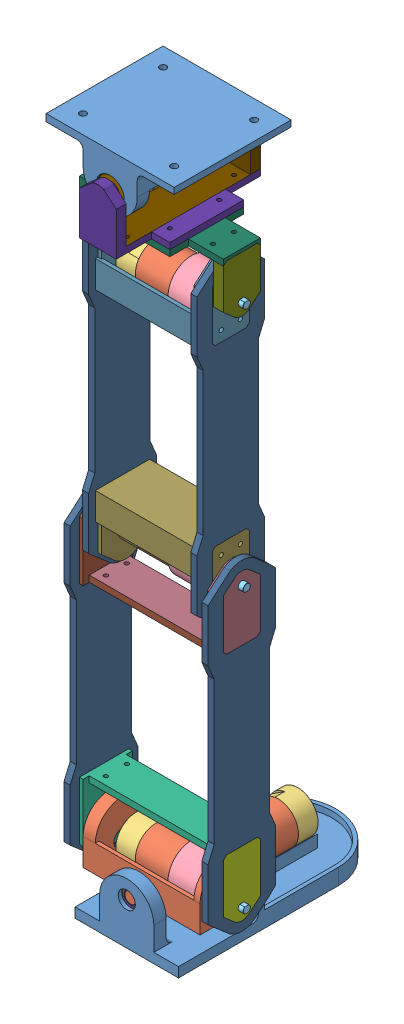
SolidWorks assembly Leg Left, configuration Default. Lengths in mm.
Overall size (121 569.75 211.17).
57 component instances, 20 part files, 77 mates.
Components (placement in the parent):
- Foot-1: Foot [Default] at origin size (89.58 49 186.67)
- Motor-1: Motor [Default] at (14.2667 22.6871 -73.752) x (-1 0 0) z (0 0 1) size (45.64 45.64 90) (flexible)
  - Motor Proper-1: Motor Proper [Default] at (14.2667 22.6871 35.252) x (0.971375 -0.237549 0) z (0 0 1) size (33 33 29)
  - Motor Encoder-1: Motor Encoder [Default] at (14.2667 22.6871 20.752) x (0.839139 0.543917 0) z (0 0 1) size (33 33 16)
  - Motor Gearbox-1: Motor Gearbox [Default] at (14.2667 22.6871 49.752) size (38 38 30)
  - Motor Shaft-1: Motor Shaft [Default] at (14.2667 15.6871 60.752) size (6 6 34)
- Motor-2: Motor [Default] at (-31.252 -0.6871 50.2667) x (0 0 -1) z (1 0 0) size (45.64 45.64 90) (flexible)
  - Motor Proper-1: Motor Proper [Default] at (14.2667 22.6871 35.252) x (0.971375 -0.237549 0) z (0 0 1) size (33 33 29)
  - Motor Encoder-1: Motor Encoder [Default] at (14.2667 22.6871 20.752) x (0.839139 0.543917 0) z (0 0 1) size (33 33 16)
  - Motor Gearbox-1: Motor Gearbox [Default] at (14.2667 22.6871 49.752) size (38 38 30)
  - Motor Shaft-1: Motor Shaft [Default] at (14.2667 15.6871 60.752) x (-1 0 0) z (0 0 1) size (6 6 34)
- Ankle Bearing-1: Ankle Bearing [Default] at (-57.5 22 36) x (0 0 -1) z (1 0 0) size (40 60 109)
- Ankle DShaft-1: Ankle DShaft [Default] at (59.5 22 36) x (0 0 1) z (-1 0 0) size (40 57.5 109)
- Bearing-1: Bearing [Default] at (-5.4134 7 64) size (30.72 30.72 6)
  - Bearing Inner-1: Bearing Inner [Default] at (5.4134 0 0) x (0.99329 0.115652 0) z (0 0 1) size (13.2 13.2 6)
  - Bearing Outer-1: Bearing Outer [Default] at (5.4134 0 0) x (0.586238 0.810139 0) z (0 0 1) size (22 22 6)
- Bearing-2: Bearing [Default] at (-43.5 14.965 30.5867) x (0 0.00646 0.999979) z (-1 0 0) size (30.72 30.72 6)
  - Bearing Inner-1: Bearing Inner [Default] at (5.4134 0 0) x (0.99329 0.115652 0) z (0 0 1) size (13.2 13.2 6)
  - Bearing Outer-1: Bearing Outer [Default] at (5.4134 0 0) x (0.586238 0.810139 0) z (0 0 1) size (22 22 6)
- Thigh and Shin-1: Thigh and Shin [Default] at (59.5 23.6603 36) x (0 0 1) z (-1 0 0) size (55 261.21 5)
- Thigh and Shin-2: Thigh and Shin [Default] at (-52.5 23.6603 36) x (0 0 1) z (-1 0 0) size (55 261.21 5)
- Knee Bearing-1: Knee Bearing [Default] at (-57.5 234.2132 36) x (0 0 1) z (1 0 0) size (40 60 109)
- Bearing-3: Bearing [Default] at (-40.5 241.2132 30.5866) x (0 0 1) z (-1 0 0) size (30.72 30.72 6)
  - Bearing Inner-1: Bearing Inner [Default] at (5.4134 0 0) x (0.99329 0.115652 0) z (0 0 1) size (13.2 13.2 6)
  - Bearing Outer-1: Bearing Outer [Default] at (5.4134 0 0) x (0.586238 0.810139 0) z (0 0 1) size (22 22 6)
- Knee-1: Knee [Default] at (50.5 248.2132 36) x (0 0 -1) z (-1 0 0) size (44 57.5 95)
- Knee DShaft-1: Knee DShaft [Default] at (59.5 234.2132 36) x (0 0 -1) z (-1 0 0) size (40 57.5 109)
- Motor-3: Motor [Default] at (-31.252 225.5261 50.2667) x (0 0 -1) z (1 0 0) size (45.64 45.64 90) (flexible)
  - Motor Proper-1: Motor Proper [Default] at (14.2667 22.6871 35.252) x (0.971375 -0.237549 0) z (0 0 1) size (33 33 29)
  - Motor Encoder-1: Motor Encoder [Default] at (14.2667 22.6871 20.752) x (0.839139 0.543917 0) z (0 0 1) size (33 33 16)
  - Motor Gearbox-1: Motor Gearbox [Default] at (14.2667 22.6871 49.752) size (38 38 30)
  - Motor Shaft-1: Motor Shaft [Default] at (14.2667 15.6871 60.752) size (6 6 34)
- Thigh and Shin-3: Thigh and Shin [Default] at (50.5 236.3735 36) x (0 0 1) z (-1 0 0) size (55 261.21 5)
- Thigh and Shin-4: Thigh and Shin [Default] at (-37.5 236.3735 36) x (0 0 1) z (-1 0 0) size (55 261.21 5)
- Hip A-1: Hip A [Default] at (50.5 433.4264 36) x (0 0 1) z (-1 0 0) size (44 57.5 95)
- Hip Bearing A-1: Hip Bearing A [Default] at (-57.5 447.4264 36) x (0 0 -1) z (1 0 0) size (60 47.81 117)
- Hip DShaft A-1: Hip DShaft A [Default] at (59.5 447.4264 36) x (0 0 1) z (-1 0 0) size (30 45 109)
- Bearing-4: Bearing [Default] at (-40.5 440.4264 30.5866) x (0 0 1) z (-1 0 0) size (30.72 30.72 6)
  - Bearing Inner-1: Bearing Inner [Default] at (5.4134 0 0) x (0.99329 0.115652 0) z (0 0 1) size (13.2 13.2 6)
  - Bearing Outer-1: Bearing Outer [Default] at (5.4134 0 0) x (0.586238 0.810139 0) z (0 0 1) size (22 22 6)
- Motor-4: Motor [Default] at (-31.252 456.1135 21.7333) x (0 0 1) z (1 0 0) size (45.64 45.64 90) (flexible)
  - Motor Proper-1: Motor Proper [Default] at (14.2667 22.6871 35.252) x (0.971375 -0.237549 0) z (0 0 1) size (33 33 29)
  - Motor Encoder-1: Motor Encoder [Default] at (14.2667 22.6871 20.752) x (0.839139 0.543917 0) z (0 0 1) size (33 33 16)
  - Motor Gearbox-1: Motor Gearbox [Default] at (14.2667 22.6871 49.752) size (38 38 30)
  - Motor Shaft-1: Motor Shaft [Default] at (14.2667 15.6871 60.752) size (6 6 34)
- Bearing-5: Bearing [Default] at (-4.4134 512.9264 80.5) size (30.72 30.72 6)
  - Bearing Inner-1: Bearing Inner [Default] at (5.4134 0 0) x (0.99329 0.115652 0) z (0 0 1) size (13.2 13.2 6)
  - Bearing Outer-1: Bearing Outer [Default] at (5.4134 0 0) x (0.586238 0.810139 0) z (0 0 1) size (22 22 6)
- Hip Bearing B-1: Hip Bearing B [Default] at (1 505.9264 94.5) x (1 0 0) z (0 0 -1) size (60 45.31 117)
- Hip DShaft B-1: Hip DShaft B [Default] at (1 505.9264 -22.5) x (-1 0 0) z (0 0 1) size (30 42.5 109)
- Motor-5: Motor [Default] at (15.2667 497.2393 68.252) x (-1 0 0) z (0 0 -1) size (45.64 45.64 90) (flexible)
  - Motor Proper-1: Motor Proper [Default] at (14.2667 22.6871 35.252) x (0.971375 -0.237549 0) z (0 0 1) size (33 33 29)
  - Motor Encoder-1: Motor Encoder [Default] at (14.2667 22.6871 20.752) x (0.839139 0.543917 0) z (0 0 1) size (33 33 16)
  - Motor Gearbox-1: Motor Gearbox [Default] at (14.2667 22.6871 49.752) size (38 38 30)
  - Motor Shaft-1: Motor Shaft [Default] at (14.2667 15.6871 60.752) size (6 6 34)
- Hip B-1: Hip B [Default] at (1 519.9264 -10.5) x (-1 0 0) z (0 0 1) size (104 44 95)
- Ankle Left-1: Ankle Left [Default] at (47.5 22 36) x (0 0 -1) z (1 0 0) size (54 47.05 95)
Mates (geometry in assembly coordinates):
- Coincident3: coordinate: point of Foot-1; point of assembly
- Concentric1: concentric aligned: cylinder of Foot-1 through (0 7 5) axis (0 0 -1) radius 7.25; cylinder of Motor-1/Motor Gearbox-1 through (0 7 6) axis (0 0 -1) radius 7
- Concentric2: concentric anti-aligned: cylinder of Foot-1 through (7.75 -13.4234 0) axis (0 0 -1) radius 1.7; cylinder of Motor-1/Motor Gearbox-1 through (7.75 -13.4234 0) axis (0 0 1) radius 1.7
- Coincident4: coincident anti-aligned: plane of Foot-1 through (0 0 0) normal (0 0 -1); plane of Motor-1/Motor Gearbox-1 through (0 0 0) normal (0 0 1)
- Concentric6: concentric anti-aligned: cylinder of Motor-2/Motor Shaft-1 through (51.5 15 36) axis (-1 0 0) radius 3; cylinder of Ankle DShaft-1 through (51.5 15 36) axis (1 0 0) radius 3
- Coincident9: coincident anti-aligned: plane of Foot-1 through (0 7 67) normal (0 0 -1); plane of Bearing-1/Bearing Outer-1 through (0 7 67) normal (0 0 1)
- Concentric7: concentric aligned: cylinder of Foot-1 through (0 7 67) axis (0 0 -1) radius 11; cylinder of Bearing-1/Bearing Outer-1 through (0 7 67) axis (0 0 -1) radius 11
- Concentric10: concentric anti-aligned: cylinder of Ankle Bearing-1 through (-41.5 15 36) axis (-1 0 0) radius 5; cylinder of Bearing-2/Bearing Inner-1 through (-46.5 15 36) axis (1 0 0) radius 5
- Coincident11: coincident anti-aligned: plane of Motor-2/Motor Shaft-1 through (63.5 17.5 36) normal (0 1 0); plane of Ankle DShaft-1 through (51.5 17.5 36) normal (0 -1 0)
- Concentric11: concentric aligned: cylinder of Ankle Bearing-1 through (44.5 60 44.5) axis (0 1 0) radius 1.6; cylinder of Ankle DShaft-1 through (44.5 57.5 44.5) axis (0 1 0) radius 1.6
- Coincident12: coincident anti-aligned: plane of Motor-2/Motor Shaft-1 through (51.5 15 36) normal (1 0 0); plane of Ankle DShaft-1 through (51.5 22 36) normal (-1 0 0)
- Coincident13: coincident anti-aligned: plane of Ankle Bearing-1 through (-52.5 57.5 48.5) normal (0 1 0); plane of Thigh and Shin-2 through (-57.5 57.5 36) normal (0 -1 0)
- Coincident14: coincident anti-aligned: plane of Ankle Bearing-1 through (-49.5 22 21) normal (0 0 -1); plane of Thigh and Shin-2 through (-57.5 23.6603 21) normal (0 0 1)
- Coincident15: coincident anti-aligned: plane of Ankle Bearing-1 through (-52.5 15 36) normal (-1 0 0); plane of Thigh and Shin-2 through (-52.5 23.6603 36) normal (1 0 0)
- Coincident16: coincident anti-aligned: plane of Ankle DShaft-1 through (-49.5 57.5 36) normal (0 1 0); plane of Thigh and Shin-1 through (54.5 57.5 36) normal (0 -1 0)
- Coincident18: coincident anti-aligned: plane of Ankle DShaft-1 through (51.5 22 51) normal (0 0 1); plane of Thigh and Shin-1 through (54.5 23.6603 51) normal (0 0 -1)
- Coincident19: coincident anti-aligned: plane of Ankle DShaft-1 through (54.5 15 36) normal (1 0 0); plane of Thigh and Shin-1 through (54.5 23.6603 36) normal (-1 0 0)
- Parallel5: parallel anti-aligned: plane of Foot-1 through (-22 -19 70) normal (0 1 0); plane of Ankle DShaft-1 through (-49.5 55 36) normal (0 -1 0)
- Coincident27: coincident anti-aligned: plane of Thigh and Shin-1 through (54.5 23.6603 21) normal (0 0 1); plane of Knee DShaft-1 through (51.5 234.2132 21) normal (0 0 -1)
- Coincident28: coincident anti-aligned: plane of Thigh and Shin-1 through (54.5 198.7132 36) normal (0 1 0); plane of Knee DShaft-1 through (-49.5 198.7132 36) normal (0 -1 0)
- Coincident29: coincident anti-aligned: plane of Thigh and Shin-1 through (54.5 23.6603 36) normal (-1 0 0); plane of Knee DShaft-1 through (54.5 241.2132 36) normal (1 0 0)
- Coincident30: coincident anti-aligned: plane of Thigh and Shin-2 through (-57.5 23.6603 21) normal (0 0 1); plane of Knee Bearing-1 through (-49.5 236.7132 21) normal (0 0 -1)
- Concentric12: concentric aligned: cylinder of Knee Bearing-1 through (-42.5 198.7132 27.5) axis (0 -1 0) radius 1.6; cylinder of Knee DShaft-1 through (-42.5 198.7132 27.5) axis (0 -1 0) radius 1.6
- Coincident32: coincident anti-aligned: plane of Knee-1 through (42.5 248.2132 36) normal (-1 0 0); plane of Motor-3/Motor Gearbox-1 through (42.5 248.2132 36) normal (1 0 0)
- Concentric14: concentric anti-aligned: cylinder of Knee-1 through (45.5 241.2132 36) axis (1 0 0) radius 7.25; cylinder of Motor-3/Motor Gearbox-1 through (48.5 241.2132 36) axis (-1 0 0) radius 7
- Concentric15: concentric aligned: cylinder of Knee-1 through (50.5 261.6366 43.75) axis (1 0 0) radius 1.7; cylinder of Motor-3/Motor Gearbox-1 through (42.5 261.6366 43.75) axis (1 0 0) radius 1.7
- Concentric17: concentric anti-aligned: cylinder of Bearing-3/Bearing Outer-1 through (-43.5 241.2132 36) axis (1 0 0) radius 11; cylinder of Knee-1 through (-37.5 241.2132 36) axis (-1 0 0) radius 11
- Coincident33: coincident anti-aligned: plane of Bearing-3/Bearing Outer-1 through (-37.5 241.2132 36) normal (1 0 0); plane of Knee-1 through (-37.5 241.2132 36) normal (-1 0 0)
- Concentric18: concentric anti-aligned: cylinder of Knee DShaft-1 through (51.5 241.2132 36) axis (1 0 0) radius 3; cylinder of Motor-3/Motor Shaft-1 through (51.5 241.2132 36) axis (-1 0 0) radius 3
- Coincident34: coincident anti-aligned: plane of Knee DShaft-1 through (51.5 238.7132 36) normal (0 1 0); plane of Motor-3/Motor Shaft-1 through (63.5 238.7132 36) normal (0 -1 0)
- Coincident35: coincident anti-aligned: plane of Knee DShaft-1 through (51.5 234.2132 36) normal (-1 0 0); plane of Motor-3/Motor Shaft-1 through (51.5 241.2132 36) normal (1 0 0)
- Parallel6: parallel aligned: plane of Foot-1 through (-22 -19 70) normal (0 1 0); plane of Knee-1 through (45.5 270.2132 14) normal (0 1 0)
- Coincident37: coincident anti-aligned: plane of Knee-1 through (45.5 248.2132 51) normal (0 0 1); plane of Thigh and Shin-3 through (45.5 236.3735 51) normal (0 0 -1)
- Coincident38: coincident anti-aligned: plane of Knee-1 through (45.5 270.2132 14) normal (0 1 0); plane of Thigh and Shin-3 through (45.5 270.2132 36) normal (0 -1 0)
- Coincident40: coincident anti-aligned: plane of Knee-1 through (45.5 248.2132 36) normal (1 0 0); plane of Thigh and Shin-3 through (45.5 236.3735 36) normal (-1 0 0)
- Coincident41: coincident anti-aligned: plane of Knee-1 through (-44.5 248.2132 21) normal (0 0 -1); plane of Thigh and Shin-4 through (-42.5 236.3735 21) normal (0 0 1)
- Coincident42: coincident anti-aligned: plane of Knee-1 through (45.5 270.2132 14) normal (0 1 0); plane of Thigh and Shin-4 through (-42.5 270.2132 36) normal (0 -1 0)
- Coincident43: coincident anti-aligned: plane of Knee-1 through (-37.5 248.2132 36) normal (-1 0 0); plane of Thigh and Shin-4 through (-37.5 236.3735 36) normal (1 0 0)
- Coincident45: coincident anti-aligned: plane of Thigh and Shin-3 through (45.5 236.3735 51) normal (0 0 -1); plane of Hip A-1 through (45.5 433.4264 51) normal (0 0 1)
- Coincident46: coincident anti-aligned: plane of Thigh and Shin-3 through (45.5 411.4264 36) normal (0 1 0); plane of Hip A-1 through (45.5 411.4264 58) normal (0 -1 0)
- Concentric19: concentric anti-aligned: cylinder of Hip A-1 through (-37.5 440.4264 36) axis (-1 0 0) radius 11; cylinder of Bearing-4/Bearing Outer-1 through (-43.5 440.4264 36) axis (1 0 0) radius 11
- Coincident47: coincident anti-aligned: plane of Hip A-1 through (-37.5 440.4264 36) normal (-1 0 0); plane of Bearing-4/Bearing Outer-1 through (-37.5 440.4264 36) normal (1 0 0)
- Concentric20: concentric anti-aligned: cylinder of Hip A-1 through (45.5 440.4264 36) axis (1 0 0) radius 7.25; cylinder of Motor-4/Motor Gearbox-1 through (48.5 440.4264 36) axis (-1 0 0) radius 7
- Concentric21: concentric aligned: cylinder of Hip A-1 through (50.5 420.003 28.25) axis (1 0 0) radius 1.7; cylinder of Motor-4/Motor Gearbox-1 through (42.5 420.003 28.25) axis (1 0 0) radius 1.7
- Coincident48: coincident anti-aligned: plane of Hip A-1 through (42.5 433.4264 36) normal (-1 0 0); plane of Motor-4/Motor Gearbox-1 through (42.5 433.4264 36) normal (1 0 0)
- Concentric22: concentric anti-aligned: cylinder of Hip DShaft A-1 through (51.5 440.4264 36) axis (1 0 0) radius 3; cylinder of Motor-4/Motor Shaft-1 through (51.5 440.4264 36) axis (-1 0 0) radius 3
- Coincident49: coincident anti-aligned: plane of Thigh and Shin-3 through (45.5 236.3735 36) normal (-1 0 0); plane of Hip A-1 through (45.5 433.4264 36) normal (1 0 0)
- Coincident50: coincident anti-aligned: plane of Hip DShaft A-1 through (51.5 442.9264 36) normal (0 -1 0); plane of Motor-4/Motor Shaft-1 through (63.5 442.9264 36) normal (0 1 0)
- Coincident51: coincident anti-aligned: plane of Hip DShaft A-1 through (51.5 447.4264 36) normal (-1 0 0); plane of Motor-4/Motor Shaft-1 through (51.5 440.4264 36) normal (1 0 0)
- Concentric23: concentric anti-aligned: cylinder of Hip Bearing A-1 through (-41.5 440.4264 36) axis (-1 0 0) radius 5; cylinder of Bearing-4/Bearing Inner-1 through (-43.5 440.4264 36) axis (1 0 0) radius 5
- Coincident53: coincident anti-aligned: plane of Hip Bearing A-1 through (59.5 475.4264 36) normal (0 -1 0); plane of Hip DShaft A-1 through (-49.5 475.4264 36) normal (0 1 0)
- Concentric24: concentric aligned: cylinder of Hip Bearing A-1 through (44.5 477.9264 27.5) axis (0 1 0) radius 1.6; cylinder of Hip DShaft A-1 through (44.5 475.4264 27.5) axis (0 1 0) radius 1.6
- Parallel7: parallel anti-aligned: plane of Foot-1 through (-22 -19 70) normal (0 1 0); plane of Hip DShaft A-1 through (-49.5 472.9264 36) normal (0 -1 0)
- Concentric27: concentric anti-aligned: cylinder of Bearing-2/Bearing Outer-1 through (-46.5 15 36) axis (1 0 0) radius 11; cylinder of Ankle Left-1 through (-40.5 15 36) axis (-1 0 0) radius 11
- Coincident56: coincident anti-aligned: plane of Bearing-2/Bearing Outer-1 through (-40.5 15 36) normal (1 0 0); plane of Ankle Left-1 through (-40.5 15 36) normal (-1 0 0)
- Coincident57: coincident anti-aligned: plane of Motor-2/Motor Gearbox-1 through (42.5 22 36) normal (1 0 0); plane of Ankle Left-1 through (42.5 22 36) normal (-1 0 0)
- Concentric29: concentric anti-aligned: cylinder of Motor-2/Motor Gearbox-1 through (48.5 15 36) axis (-1 0 0) radius 7; cylinder of Ankle Left-1 through (42.5 15 36) axis (1 0 0) radius 7.25
- Concentric30: concentric aligned: cylinder of Motor-2/Motor Gearbox-1 through (42.5 35.4234 43.75) axis (1 0 0) radius 1.7; cylinder of Ankle Left-1 through (47.5 35.4234 43.75) axis (1 0 0) radius 1.7
- Concentric31: concentric aligned: cylinder of Bearing-1/Bearing Inner-1 through (0 7 67) axis (0 0 -1) radius 5; cylinder of Ankle Left-1 through (0 7 67) axis (0 0 -1) radius 5
- Coincident58: coincident anti-aligned: plane of Motor-1/Motor Shaft-1 through (0 7 21) normal (0 0 1); plane of Ankle Left-1 through (0 7 21) normal (0 0 -1)
- Concentric32: concentric anti-aligned: cylinder of Bearing-5/Bearing Outer-1 through (1 512.9264 83.5) axis (0 0 -1) radius 11; cylinder of Hip B-1 through (1 512.9264 77.5) axis (0 0 1) radius 11
- Coincident59: coincident anti-aligned: plane of Bearing-5/Bearing Outer-1 through (1 512.9264 77.5) normal (0 0 -1); plane of Hip B-1 through (1 512.9264 77.5) normal (0 0 1)
- Concentric36: concentric anti-aligned: cylinder of Motor-5/Motor Gearbox-1 through (1 512.9264 -11.5) axis (0 0 1) radius 7; cylinder of Hip B-1 through (1 512.9264 -5.5) axis (0 0 -1) radius 7.25
- Concentric37: concentric aligned: cylinder of Motor-5/Motor Gearbox-1 through (-6.75 533.3498 -5.5) axis (0 0 -1) radius 1.7; cylinder of Hip B-1 through (-6.75 533.3498 -10.5) axis (0 0 -1) radius 1.7
- Coincident61: coincident anti-aligned: plane of Motor-5/Motor Gearbox-1 through (1 519.9264 -5.5) normal (0 0 -1); plane of Hip B-1 through (1 519.9264 -5.5) normal (0 0 1)
- Coincident62: coincident anti-aligned: plane of Hip Bearing A-1 through (59.5 477.9264 36) normal (0 1 0); plane of Hip Bearing B-1 through (1 477.9264 -22.5) normal (0 -1 0)
- Coincident63: coincident anti-aligned: plane of Hip Bearing A-1 through (59.5 477.9264 36) normal (0 1 0); plane of Hip Bearing B-1 through (1 477.9264 -22.5) normal (0 -1 0)
- Concentric38: concentric anti-aligned: cylinder of Hip Bearing A-1 through (-19 477.9264 16) axis (0 1 0) radius 1.6; cylinder of Hip Bearing B-1 through (-19 477.9264 16) axis (0 -1 0) radius 1.6
- Concentric39: concentric anti-aligned: cylinder of Hip Bearing A-1 through (21 477.9264 56) axis (0 1 0) radius 1.6; cylinder of Hip Bearing B-1 through (21 477.9264 56) axis (0 -1 0) radius 1.6
- Coincident64: coincident anti-aligned: plane of Hip Bearing B-1 through (1 480.4264 -22.5) normal (0 1 0); plane of Hip DShaft B-1 through (1 480.4264 86.5) normal (0 -1 0)
- Concentric40: concentric aligned: cylinder of Hip Bearing B-1 through (9.5 477.9264 79.5) axis (0 -1 0) radius 1.6; cylinder of Hip DShaft B-1 through (9.5 480.4264 79.5) axis (0 -1 0) radius 1.6
- Concentric41: concentric aligned: cylinder of Hip Bearing B-1 through (-7.5 477.9264 -7.5) axis (0 -1 0) radius 1.6; cylinder of Hip DShaft B-1 through (-7.5 480.4264 -7.5) axis (0 -1 0) radius 1.6
- Concentric42: concentric anti-aligned: cylinder of Hip DShaft B-1 through (1 512.9264 -14.5) axis (0 0 -1) radius 3; cylinder of Motor-5/Motor Shaft-1 through (1 512.9264 -14.5) axis (0 0 1) radius 3
- Coincident65: coincident anti-aligned: plane of Hip DShaft B-1 through (1 510.4264 -14.5) normal (0 1 0); plane of Motor-5/Motor Shaft-1 through (1 510.4264 -26.5) normal (0 -1 0)
- Coincident66: coincident anti-aligned: plane of Hip DShaft B-1 through (1 505.9264 -14.5) normal (0 0 1); plane of Motor-5/Motor Shaft-1 through (1 512.9264 -14.5) normal (0 0 -1)
- Parallel9: parallel anti-aligned: plane of Foot-1 through (-22 -19 70) normal (0 1 0); plane of Hip B-1 through (53 536.9264 -10.5) normal (0 -1 0)
- Coincident67: coincident anti-aligned: plane of Thigh and Shin-2 through (-57.5 198.7132 36) normal (0 1 0); plane of Knee Bearing-1 through (-52.5 198.7132 23.5) normal (0 -1 0)
